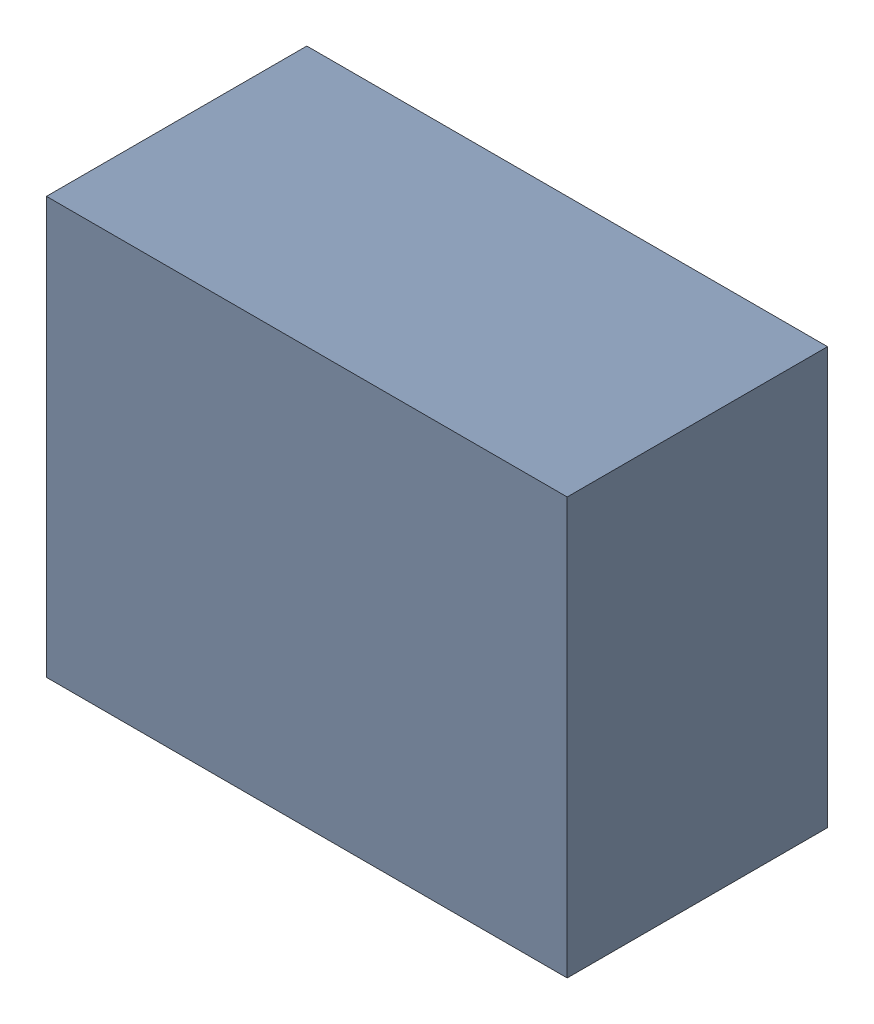
SolidWorks assembly D6, configuration Default. Lengths in mm.
Overall size (1 0.8 0.5).
2 component instances, 1 part files, 0 mates.
Components (placement in the parent):
- 870940960-1: 870940960 [Default] at (41.166 32.031 0) size (1 0.8 0.5)
  - Extruded_33-1: Extruded_33 [Default] at origin size (1 0.8 0.5)
